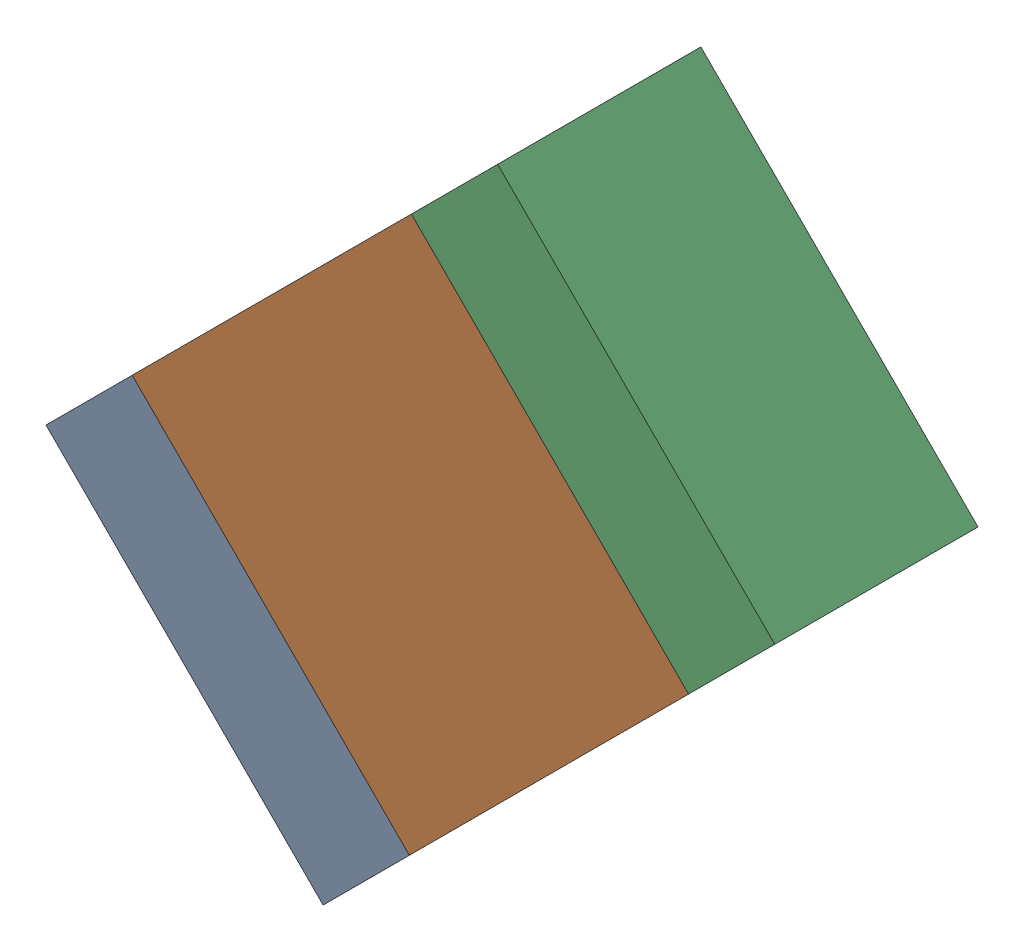
SolidWorks assembly R8-2, configuration Default. Lengths in mm.
Overall size (2.51 2.51 0.7).
6 component instances, 2 part files, 0 mates.
Components (placement in the parent):
- 959207576-2-1: 959207576-2 [Default] at (78.6187 92.1936 0) size (1.25 1.25 0.7)
  - Extruded-85-1: Extruded-85 [Default] at origin size (1.25 1.25 0.7)
- 959207712-2-1: 959207712-2 [Default] at (79.248 92.8229 0) size (1.92 1.92 0.7)
  - Extruded-86-1: Extruded-86 [Default] at origin size (1.92 1.92 0.7)
- 959207576-2-2: 959207576-2 [Default] at (79.8773 93.4522 0) size (1.25 1.25 0.7)
  - Extruded-85-1: Extruded-85 [Default] at origin size (1.25 1.25 0.7)
